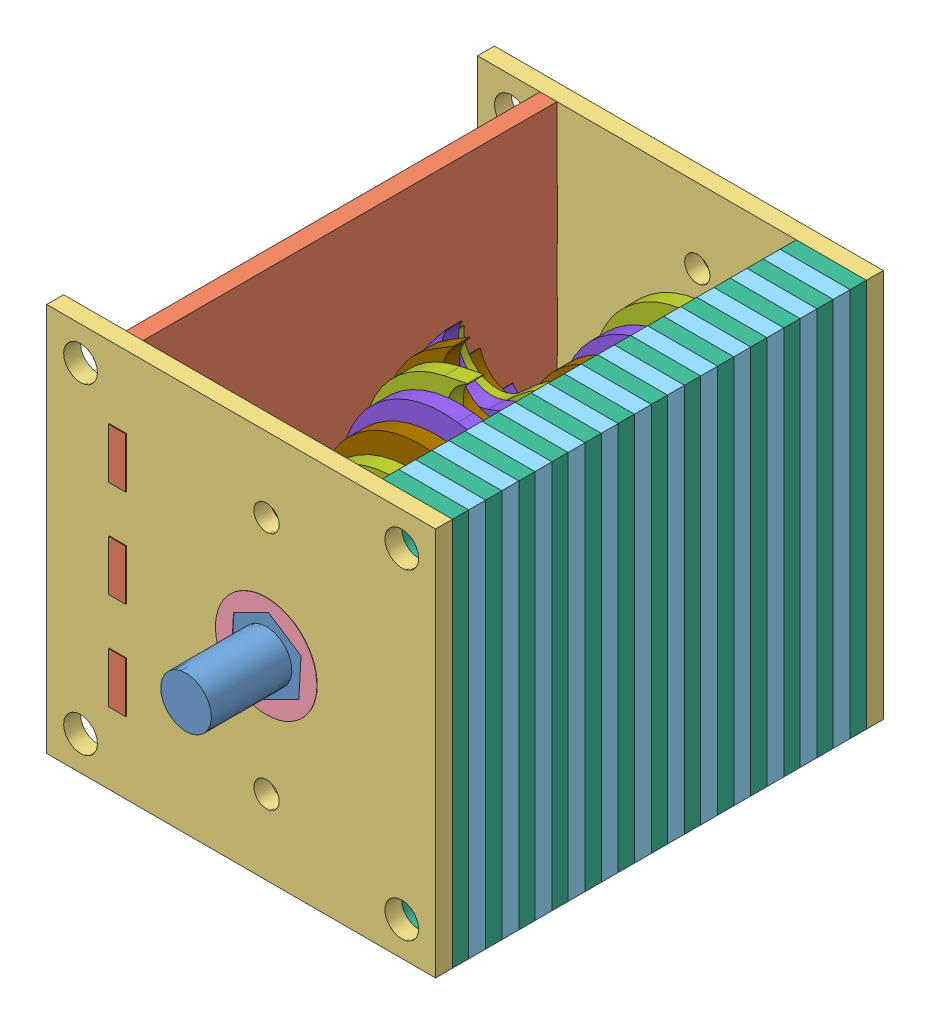
SolidWorks assembly Assembly_Single_Cutter, configuration Default. Lengths in mm.
Overall size (146.05 146.05 228.6).
57 component instances, 9 part files, 49 mates.
Components (placement in the parent):
- Axle-1: Axle [Default] at (0 0 80.899) x (0.998227 -0.059519 0) z (0 0 1) size (25.4 29.33 228.6)
- BackPlate-1: BackPlate [Default] at (-55.88 0 80.899) x (0 0 -1) z (1 0 0) size (168.66 146.05 6.35)
- Side_Plate-1: Side_Plate [Default] at origin size (146.05 146.05 6.35)
- Side_Plate-2: Side_Plate [Default] at (0 0 161.798) size (146.05 146.05 6.35)
- Hex_Spacer-1: Hex_Spacer [Default] at (0 0 31.115) x (0.550659 0.834731 0) z (0 0 1) size (38.1 38.1 6.35)
- Hex_Spacer-2: Hex_Spacer [Default] at (0 0 18.669) x (0.550659 0.834731 0) z (0 0 1) size (38.1 38.1 6.35)
- Hex_Spacer-3: Hex_Spacer [Default] at (0 0 80.899) x (-0.550659 -0.834731 0) z (0 0 1) size (38.1 38.1 6.35)
- Hex_Spacer-13: Hex_Spacer [Default] at (0 0 6.223) x (0.550659 0.834731 0) z (0 0 1) size (38.1 38.1 6.35)
- Hex_Spacer-14: Hex_Spacer [Default] at (0 0 -0.127) x (0.550659 0.834731 0) z (0 0 1) size (38.1 38.1 6.35)
- Hex_Spacer-15: Hex_Spacer [Default] at (0 0 161.925) x (0.550659 0.834731 0) z (0 0 1) size (38.1 38.1 6.35)
- Spacer_1-1: Spacer_1 [Default] at (44.45 0 12.446) size (34.77 146.05 6.35)
- Spacer_2-1: Spacer_2 [Default] at (44.45 0 6.223) size (59.73 146.05 6.1)
- Spacer_2-14: Spacer_2 [Default] at (44.45 0 155.575) size (59.73 146.05 6.1)
- Spacer_2-2: Spacer_2 [Default] at (44.45 0 18.669) size (59.73 146.05 6.1)
- Spacer_2-3: Spacer_2 [Default] at (44.45 0 31.115) size (59.73 146.05 6.1)
- Spacer_2-4: Spacer_2 [Default] at (44.45 0 43.561) size (59.73 146.05 6.1)
- Spacer_2-5: Spacer_2 [Default] at (44.45 0 56.007) size (59.73 146.05 6.1)
- Spacer_2-6: Spacer_2 [Default] at (44.45 0 68.453) size (59.73 146.05 6.1)
- Spacer_2-7: Spacer_2 [Default] at (44.45 0 80.899) size (59.73 146.05 6.1)
- Spacer_2-8: Spacer_2 [Default] at (44.45 0 93.345) size (59.73 146.05 6.1)
- Spacer_2-9: Spacer_2 [Default] at (44.45 0 105.791) size (59.73 146.05 6.1)
- Spacer_2-10: Spacer_2 [Default] at (44.45 0 118.237) size (59.73 146.05 6.1)
- Spacer_2-11: Spacer_2 [Default] at (44.45 0 130.683) size (59.73 146.05 6.1)
- Spacer_2-12: Spacer_2 [Default] at (44.45 0 143.129) size (59.73 146.05 6.1)
- Spacer_1-3: Spacer_1 [Default] at (44.45 0 24.892) size (34.77 146.05 6.35)
- Spacer_1-4: Spacer_1 [Default] at (44.45 0 37.338) size (34.77 146.05 6.35)
- Spacer_1-5: Spacer_1 [Default] at (44.45 0 49.784) size (34.77 146.05 6.35)
- Spacer_1-6: Spacer_1 [Default] at (44.45 0 62.23) size (34.77 146.05 6.35)
- Spacer_1-7: Spacer_1 [Default] at (44.45 0 74.676) size (34.77 146.05 6.35)
- Spacer_1-8: Spacer_1 [Default] at (44.45 0 87.122) size (34.77 146.05 6.35)
- Spacer_1-9: Spacer_1 [Default] at (44.45 0 99.568) size (34.77 146.05 6.35)
- Spacer_1-10: Spacer_1 [Default] at (44.45 0 112.014) size (34.77 146.05 6.35)
- Spacer_1-11: Spacer_1 [Default] at (44.45 0 124.46) size (34.77 146.05 6.35)
- Spacer_1-12: Spacer_1 [Default] at (44.45 0 136.906) size (34.77 146.05 6.35)
- Spacer_1-13: Spacer_1 [Default] at (44.45 0 149.352) size (34.77 146.05 6.35)
- 2Tooth_Cutter_V1-1: 2Tooth_Cutter_V1 [Default] at (0 0 12.446) x (-0.447568 0.89425 0) z (0 0 1) size (75.28 102.63 6.1)
- 2Tooth_Cutter_V1_2-1: 2Tooth_Cutter_V1_2 [Default] at (0 0 24.892) x (-0.114725 0.993397 0) z (0 0 1) size (75.28 102.63 6.1)
- 2Tooth_Cutter_V1_3-1: 2Tooth_Cutter_V1_3 [Default] at (0 0 37.338) x (0.231955 0.972726 0) z (0 0 1) size (75.28 102.63 6.1)
- Hex_Spacer-20: Hex_Spacer [Default] at (0 0 68.453) x (0.998227 -0.059519 0) z (0 0 1) size (38.1 38.1 6.35)
- Hex_Spacer-21: Hex_Spacer [Default] at (0 0 56.007) x (0.998227 -0.059519 0) z (0 0 1) size (38.1 38.1 6.35)
- Hex_Spacer-22: Hex_Spacer [Default] at (0 0 43.561) x (0.998227 -0.059519 0) z (0 0 1) size (38.1 38.1 6.35)
- 2Tooth_Cutter_V1_3-3: 2Tooth_Cutter_V1_3 [Default] at (0 0 74.676) x (0.958383 0.285484 0) z (0 0 1) size (75.28 102.63 6.1)
- 2Tooth_Cutter_V1_2-3: 2Tooth_Cutter_V1_2 [Default] at (0 0 62.23) x (0.802945 0.596054 0) z (0 0 1) size (75.28 102.63 6.1)
- 2Tooth_Cutter_V1-3: 2Tooth_Cutter_V1 [Default] at (0 0 49.784) x (0.550659 0.834731 0) z (0 0 1) size (75.28 102.63 6.1)
- 2Tooth_Cutter_V1-4: 2Tooth_Cutter_V1 [Default] at (0 0 87.122) x (0.998227 -0.059519 0) z (0 0 1) size (75.28 102.63 6.1)
- 2Tooth_Cutter_V1-5: 2Tooth_Cutter_V1 [Default] at (0 0 124.46) x (0.447568 -0.89425 0) z (0 0 1) size (75.28 102.63 6.1)
- 2Tooth_Cutter_V1_2-4: 2Tooth_Cutter_V1_2 [Default] at (0 0 99.568) x (0.91767 -0.397344 0) z (0 0 1) size (75.28 102.63 6.1)
- 2Tooth_Cutter_V1_2-5: 2Tooth_Cutter_V1_2 [Default] at (0 0 136.906) x (0.114725 -0.993397 0) z (0 0 1) size (75.28 102.63 6.1)
- 2Tooth_Cutter_V1_3-4: 2Tooth_Cutter_V1_3 [Default] at (0 0 112.014) x (0.726428 -0.687242 0) z (0 0 1) size (75.28 102.63 6.1)
- 2Tooth_Cutter_V1_3-5: 2Tooth_Cutter_V1_3 [Default] at (0 0 149.352) x (-0.231955 -0.972726 0) z (0 0 1) size (75.28 102.63 6.1)
- Hex_Spacer-23: Hex_Spacer [Default] at (0 0 80.899) x (0.447568 -0.89425 0) z (0 0 1) size (38.1 38.1 6.35)
- Hex_Spacer-24: Hex_Spacer [Default] at (0 0 118.237) x (-0.550659 -0.834731 0) z (0 0 1) size (38.1 38.1 6.35)
- Hex_Spacer-25: Hex_Spacer [Default] at (0 0 93.345) x (0.447568 -0.89425 0) z (0 0 1) size (38.1 38.1 6.35)
- Hex_Spacer-26: Hex_Spacer [Default] at (0 0 130.683) x (-0.550659 -0.834731 0) z (0 0 1) size (38.1 38.1 6.35)
- Hex_Spacer-27: Hex_Spacer [Default] at (0 0 105.791) x (0.447568 -0.89425 0) z (0 0 1) size (38.1 38.1 6.35)
- Hex_Spacer-28: Hex_Spacer [Default] at (0 0 143.129) x (-0.550659 -0.834731 0) z (0 0 1) size (38.1 38.1 6.35)
- Hex_Spacer-29: Hex_Spacer [Default] at (0 0 155.575) x (0.550659 0.834731 0) z (0 0 1) size (38.1 38.1 6.35)
Mates (geometry in assembly coordinates):
- Coincident15: coincident: plane of BackPlate-1 through (-55.88 0 80.899) normal (0 1 0); plane of assembly through (0 0 0) normal (0 1 0)
- Coincident19: coincident: plane of Side_Plate-1 through (0 0 0) normal (0 0 1); plane of assembly through (0 0 0) normal (0 0 1)
- Coincident20: coincident: plane of Side_Plate-1 through (0 0 0) normal (1 0 0); plane of assembly through (0 0 0) normal (1 0 0)
- Coincident21: coincident: plane of Side_Plate-1 through (0 0 0) normal (0 1 0); plane of assembly through (0 0 0) normal (0 1 0)
- Coincident22: coincident: plane of BackPlate-1 through (-55.88 0 80.899) normal (1 0 0); plane of assembly through (-55.88 0 0) normal (1 0 0)
- Coincident23: coincident: plane of BackPlate-1 through (-52.705 73.025 3.175) normal (0 0 -1); plane of Side_Plate-1 through (0 0 3.175) normal (0 0 1)
- Concentric9: concentric: cylinder of Axle-1 through (0 0 195.199) axis (0 0 -1) radius 9.525; cylinder of Side_Plate-1 through (0 0 3.175) axis (0 0 -1) radius 19.05
- Coincident25: coincident: line of Axle-1 through (-13.1139 -6.5635 164.973) axis (0 0 -1); line of Hex_Spacer-1 through (-13.1139 -6.5635 34.29) axis (0 0 -1)
- Coincident26: coincident: line of Axle-1 through (13.1139 6.5635 164.973) axis (0 0 -1); line of Hex_Spacer-1 through (13.1139 6.5635 34.29) axis (0 0 -1)
- Concentric14: concentric: cylinder of Side_Plate-1 through (50.8 -60.325 3.175) axis (0 0 -1) radius 6.35; cylinder of Spacer_1-1 through (50.8 -60.325 15.621) axis (0 0 -1) radius 6.3627
- Concentric15: concentric: cylinder of Side_Plate-1 through (50.8 60.325 3.175) axis (0 0 -1) radius 6.35; cylinder of Spacer_1-1 through (50.8 60.325 15.621) axis (0 0 -1) radius 6.3627
- Concentric16: concentric: cylinder of Side_Plate-1 through (50.8 60.325 3.175) axis (0 0 -1) radius 6.35; cylinder of Spacer_2-1 through (50.8 60.325 9.271) axis (0 0 -1) radius 6.3627
- Concentric17: concentric: cylinder of Side_Plate-1 through (50.8 -60.325 3.175) axis (0 0 -1) radius 6.35; cylinder of Spacer_2-1 through (50.8 -60.325 9.271) axis (0 0 -1) radius 6.3627
- Coincident38: coincident: plane of Side_Plate-1 through (0 0 3.175) normal (0 0 1); plane of Spacer_2-1 through (44.45 0 3.175) normal (0 0 -1)
- Coincident39: coincident: plane of Spacer_1-1 through (44.45 0 9.271) normal (0 0 -1); plane of Spacer_2-1 through (44.45 0 9.271) normal (0 0 1)
- Coincident40: coincident: plane of Spacer_1-13 through (44.45 0 152.527) normal (0 0 1); plane of Spacer_2-14 through (44.45 0 152.527) normal (0 0 -1)
- Concentric19: concentric: cylinder of Side_Plate-1 through (50.8 -60.325 3.175) axis (0 0 -1) radius 6.35; cylinder of Spacer_2-14 through (50.8 -60.325 158.623) axis (0 0 -1) radius 6.3627
- Concentric20: concentric: cylinder of Side_Plate-1 through (50.8 60.325 3.175) axis (0 0 -1) radius 6.35; cylinder of Spacer_2-14 through (50.8 60.325 158.623) axis (0 0 -1) radius 6.3627
- Coincident41: coincident: plane of Spacer_2-14 through (44.45 0 158.623) normal (0 0 1); plane of Side_Plate-2 through (0 0 158.623) normal (0 0 -1)
- Concentric22: concentric: cylinder of Side_Plate-1 through (50.8 60.325 3.175) axis (0 0 -1) radius 6.35; cylinder of Side_Plate-2 through (50.8 60.325 164.973) axis (0 0 -1) radius 6.35
- Concentric23: concentric: cylinder of Side_Plate-1 through (50.8 -60.325 3.175) axis (0 0 -1) radius 6.35; cylinder of Side_Plate-2 through (50.8 -60.325 164.973) axis (0 0 -1) radius 6.35
- Coincident44: coincident: line of Axle-1 through (0.8728 14.6387 164.973) axis (0 0 -1); line of Hex_Spacer-2 through (0.8728 14.6387 21.844) axis (0 0 -1)
- Coincident45: coincident: line of Axle-1 through (-0.8728 -14.6387 164.973) axis (0 0 -1); line of Hex_Spacer-2 through (-0.8728 -14.6387 21.844) axis (0 0 -1)
- Coincident54: coincident: line of Axle-1 through (12.2411 -8.0752 164.973) axis (0 0 -1); line of Hex_Spacer-3 through (12.2411 -8.0752 84.074) axis (0 0 -1)
- Coincident55: coincident: line of Axle-1 through (0.8728 14.6387 164.973) axis (0 0 -1); line of Hex_Spacer-3 through (0.8728 14.6387 84.074) axis (0 0 -1)
- Coincident57: coincident: plane of Axle-1 through (0 0 -3.175) normal (0 0 -1); plane of Side_Plate-1 through (0 0 -3.175) normal (0 0 -1)
- Coincident58: coincident: line of Axle-1 through (0.8728 14.6387 164.973) axis (0 0 -1); line of Hex_Spacer-13 through (0.8728 14.6387 9.398) axis (0 0 -1)
- Coincident59: coincident: line of Axle-1 through (-0.8728 -14.6387 164.973) axis (0 0 -1); line of Hex_Spacer-13 through (-0.8728 -14.6387 9.398) axis (0 0 -1)
- Coincident61: coincident: line of Axle-1 through (0.8728 14.6387 164.973) axis (0 0 -1); line of Hex_Spacer-14 through (0.8728 14.6387 3.048) axis (0 0 -1)
- Coincident62: coincident: line of Axle-1 through (-0.8728 -14.6387 164.973) axis (0 0 -1); line of Hex_Spacer-14 through (-0.8728 -14.6387 3.048) axis (0 0 -1)
- Coincident63: coincident: plane of Hex_Spacer-13 through (0 0 3.048) normal (0 0 -1); plane of Hex_Spacer-14 through (0 0 3.048) normal (0 0 1)
- Coincident64: coincident: line of Axle-1 through (0.8728 14.6387 164.973) axis (0 0 -1); line of Hex_Spacer-15 through (0.8728 14.6387 165.1) axis (0 0 -1)
- Coincident65: coincident: line of Axle-1 through (-0.8728 -14.6387 164.973) axis (0 0 -1); line of Hex_Spacer-15 through (-0.8728 -14.6387 165.1) axis (0 0 -1)
- Coincident69: coincident: plane of Spacer_1-1 through (44.45 0 12.446) normal (0 0 1); plane of 2Tooth_Cutter_V1-1 through (0 0 12.446) normal (0 0 1); plane of ?; plane of ?; plane of ?
- Parallel1: parallel: line of Axle-1 through (12.2411 -8.0752 164.973) axis (0 0 -1); line of 2Tooth_Cutter_V1_2-1 through (-12.2411 8.0752 27.94) axis (0 0 -1)
- Coincident80: coincident: line of Axle-1 through (-12.2411 8.0752 164.973) axis (0 0 -1); line of 2Tooth_Cutter_V1-1 through (-12.2411 8.0752 15.494) axis (0 0 -1); plane of ?; plane of ?; plane of ?
- Coincident81: coincident: line of Axle-1 through (-0.8728 -14.6387 164.973) axis (0 0 -1); line of 2Tooth_Cutter_V1-1 through (-0.8728 -14.6387 15.494) axis (0 0 -1); plane of ?; plane of ?; plane of ?
- Coincident82: coincident: line of Axle-1 through (-12.2411 8.0752 164.973) axis (0 0 -1); line of 2Tooth_Cutter_V1_2-1 through (-12.2411 8.0752 27.94) axis (0 0 -1)
- Coincident83: coincident: line of Axle-1 through (-0.8728 -14.6387 164.973) axis (0 0 -1); line of 2Tooth_Cutter_V1_2-1 through (-0.8728 -14.6387 27.94) axis (0 0 -1)
- Coincident84: coincident: plane of Hex_Spacer-2 through (0 0 21.844) normal (0 0 1); plane of 2Tooth_Cutter_V1_2-1 through (0 0 21.844) normal (0 0 -1)
- Coincident85: coincident: plane of Hex_Spacer-2 through (0 0 15.494) normal (0 0 -1); plane of 2Tooth_Cutter_V1-1 through (0 0 15.494) normal (0 0 1); plane of ?; plane of ?; plane of ?
- Coincident87: coincident: line of Axle-1 through (-12.2411 8.0752 164.973) axis (0 0 -1); line of 2Tooth_Cutter_V1_3-1 through (-12.2411 8.0752 40.386) axis (0 0 -1)
- Coincident88: coincident: line of Axle-1 through (-0.8728 -14.6387 164.973) axis (0 0 -1); line of 2Tooth_Cutter_V1_3-1 through (-0.8728 -14.6387 40.386) axis (0 0 -1)
- Coincident89: coincident: plane of Hex_Spacer-1 through (0 0 27.94) normal (0 0 -1); plane of 2Tooth_Cutter_V1_2-1 through (0 0 27.94) normal (0 0 1)
- Coincident90: coincident: plane of Hex_Spacer-1 through (0 0 34.29) normal (0 0 1); plane of 2Tooth_Cutter_V1_3-1 through (0 0 34.29) normal (0 0 -1)
- Coincident91: coincident: plane of Hex_Spacer-3 through (0 0 77.724) normal (0 0 -1); plane of 2Tooth_Cutter_V1_3-3 through (0 0 77.724) normal (0 0 1)
- Coincident92: coincident: line of Axle-1 through (12.2411 -8.0752 164.973) axis (0 0 -1); line of Hex_Spacer-29 through (12.2411 -8.0752 158.75) axis (0 0 -1)
- Coincident93: coincident: line of Axle-1 through (13.1139 6.5635 164.973) axis (0 0 -1); line of Hex_Spacer-29 through (13.1139 6.5635 158.75) axis (0 0 -1)
- Coincident94: coincident: plane of 2Tooth_Cutter_V1_3-5 through (0 0 152.4) normal (0 0 1); plane of Hex_Spacer-29 through (0 0 152.4) normal (0 0 -1)
